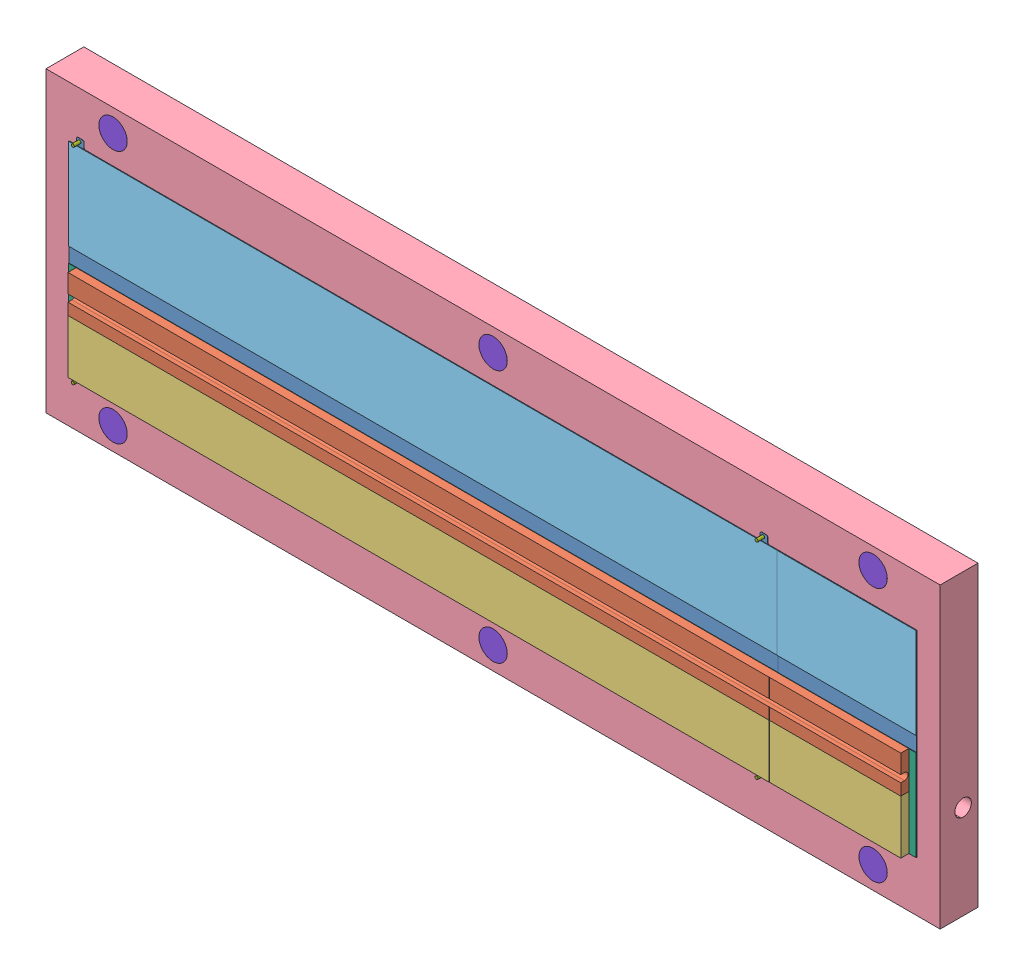
SolidWorks assembly IST Grind Fixture, configuration Default. Lengths in mm.
Overall size (600 200 31.36).
16 component instances, 8 part files, 35 mates.
Components (placement in the parent):
- Flattened Kapton-1: Flattened Kapton [Default] at (-288.1719 96.9459 86.2007) size (568.82 142.03 0.23)
- IST CFoam Stave rev 6_10-1: IST CFoam Stave rev 6_10 [Default] at (-8.6979 13.4546 89.4122) x (0 -1 0) z (1 0 0) size (25 5.5 558.8)
- IST Choneycomb Stave rev6_10-1: IST Choneycomb Stave rev6_10 [Default] at (-288.0979 -17.0454 89.4122) x (0 1 0) z (1 0 0) size (36 5.5 558.8)
- IST Grind Fixture-1: IST Grind Fixture [Default] at (-308.7819 -69.0041 60.8007) x (1 0 0) z (0 -1 0) size (600 25.4 200)
- IST CF skin rev 6_10 connector side-1: IST CF skin rev 6_10 connector side [Default] at (-8.7719 66.446 86.3622) x (-1 0 0) z (0 1 0) size (568.8 0.37 61)
- IST CF skin rev 6_10-1: IST CF skin rev 6_10 [Default] at (-8.7719 -4.554 86.6622) x (1 0 0) z (0 1 0) size (568.8 0.37 61)
- 2mm x 30mm pin-1: 2mm x 30mm pin [Default] at (172.6281 99.9459 90.8007) x (1 0 0) z (0 1 0) size (2 30 2)
- 2mm x 30mm pin-2: 2mm x 30mm pin [Default] at (172.6281 -38.0541 90.8007) x (1 0 0) z (0 1 0) size (2 30 2)
- 2mm x 30mm pin-3: 2mm x 30mm pin [Default] at (-286.1719 -38.0541 90.8007) x (1 0 0) z (0 1 0) size (2 30 2)
- 2mm x 30mm pin-4: 2mm x 30mm pin [Default] at (-286.1719 99.9459 90.8007) x (1 0 0) z (0 1 0) size (2 30 2)
- Steel Plug-1: Steel Plug [Default] at (246.2181 -54.0041 60.8007) x (1 0 0) z (0 -1 0) size (19.05 25.4 19.05)
- Steel Plug-2: Steel Plug [Default] at (-8.7819 -54.0041 60.8007) x (1 0 0) z (0 -1 0) size (19.05 25.4 19.05)
- Steel Plug-3: Steel Plug [Default] at (-263.7819 -54.0041 60.8007) x (1 0 0) z (0 -1 0) size (19.05 25.4 19.05)
- Steel Plug-4: Steel Plug [Default] at (-263.7819 115.9959 60.8007) x (1 0 0) z (0 -1 0) size (19.05 25.4 19.05)
- Steel Plug-5: Steel Plug [Default] at (-8.7819 115.9959 60.8007) x (1 0 0) z (0 -1 0) size (19.05 25.4 19.05)
- Steel Plug-6: Steel Plug [Default] at (246.2181 116.9959 60.8007) x (1 0 0) z (0 -1 0) size (19.05 25.4 19.05)
Mates (geometry in assembly coordinates):
- Distance1: distance = 0.076 mm anti-aligned: plane of IST CFoam Stave rev 6_10-1 through (182.4521 0.9546 92.1622) normal (1 0 0); plane of Flattened Kapton-1 through (182.5281 30.9503 86.4307) normal (-1 0 0)
- Distance2: distance = 0.076 mm anti-aligned: plane of IST Choneycomb Stave rev6_10-1 through (182.4521 -35.0454 86.6622) normal (1 0 0); plane of Flattened Kapton-1 through (182.5281 30.9503 86.4307) normal (-1 0 0)
- Coincident12: coincident aligned: plane of Flattened Kapton-1 through (-464.9409 -35.0454 86.3607) normal (0 -1 0); plane of IST Choneycomb Stave rev6_10-1 through (270.7021 -35.0454 92.1622) normal (0 -1 0)
- Coincident13: coincident anti-aligned: plane of IST CFoam Stave rev 6_10-1 through (250.7021 0.9546 86.6622) normal (0 -1 0); plane of IST Choneycomb Stave rev6_10-1 through (270.7021 0.9546 92.1622) normal (0 1 0)
- Coincident14: coincident anti-aligned: plane of Flattened Kapton-1 through (-464.9409 30.9503 86.2007) normal (0 0 -1); plane of IST Grind Fixture-1 through (-308.7819 130.9959 86.2007) normal (0 0 1)
- Concentric1: concentric aligned: cylinder of Flattened Kapton-1 through (172.6281 -38.0541 86.3607) axis (0 0 -1) radius 1; cylinder of IST Grind Fixture-1 through (172.6281 -38.0541 86.2007) axis (0 0 -1) radius 1
- Concentric2: concentric aligned: cylinder of Flattened Kapton-1 through (-286.1719 -38.0541 86.3607) axis (0 0 -1) radius 1; cylinder of IST Grind Fixture-1 through (-286.1719 -38.0541 86.2007) axis (0 0 -1) radius 1
- Coincident15: coincident anti-aligned: plane of Flattened Kapton-1 through (-464.9409 30.9503 86.4307) normal (0 0 1); plane of IST CF skin rev 6_10 connector side-1 through (275.6281 35.9459 86.4307) normal (0 0 -1)
- Coincident16: coincident aligned: plane of Flattened Kapton-1 through (275.6281 30.9503 86.4307) normal (1 0 0); plane of IST CF skin rev 6_10 connector side-1 through (275.6281 35.946 22.1671) normal (1 0 0)
- Coincident17: coincident aligned: plane of Flattened Kapton-1 through (-464.9409 96.946 86.4307) normal (0 1 0); plane of IST CF skin rev 6_10 connector side-1 through (255.6281 96.946 86.6622) normal (0 1 0)
- Coincident20: coincident anti-aligned: plane of Flattened Kapton-1 through (-464.9409 30.9503 86.4307) normal (0 0 1); plane of IST CF skin rev 6_10-1 through (275.6281 25.946 86.4307) normal (0 0 -1)
- Coincident21: coincident aligned: plane of Flattened Kapton-1 through (-464.9409 -35.054 86.3607) normal (0 -1 0); plane of IST CF skin rev 6_10-1 through (-273.1719 -35.054 86.3622) normal (0 -1 0)
- Coincident22: coincident aligned: plane of Flattened Kapton-1 through (275.6281 30.9503 86.4307) normal (1 0 0); plane of IST CF skin rev 6_10-1 through (275.6281 -35.054 150.8572) normal (1 0 0)
- Coincident24: coincident anti-aligned: plane of IST Choneycomb Stave rev6_10-1 through (270.7021 -35.0454 86.7307) normal (0 0 -1); plane of IST CF skin rev 6_10-1 through (182.3781 -128.3041 86.7307) normal (0 0 1)
- Coincident25: coincident anti-aligned: plane of IST CFoam Stave rev 6_10-1 through (270.7021 0.9546 86.7307) normal (0 0 -1); plane of IST CF skin rev 6_10-1 through (182.3781 -128.3041 86.7307) normal (0 0 1)
- Concentric3: concentric anti-aligned: cylinder of IST Grind Fixture-1 through (172.6281 99.9459 86.2007) axis (0 0 -1) radius 1; cylinder of 2mm x 30mm pin-1 through (172.6281 99.9459 60.8007) axis (0 0 1) radius 1
- Coincident26: coincident aligned: plane of IST Grind Fixture-1 through (-308.7819 130.9959 60.8007) normal (0 0 -1); plane of 2mm x 30mm pin-1 through (172.6281 99.9459 60.8007) normal (0 0 -1)
- Concentric4: concentric anti-aligned: cylinder of IST Grind Fixture-1 through (172.6281 -38.0541 86.2007) axis (0 0 -1) radius 1; cylinder of 2mm x 30mm pin-2 through (172.6281 -38.0541 60.8007) axis (0 0 1) radius 1
- Coincident27: coincident aligned: plane of IST Grind Fixture-1 through (-308.7819 130.9959 60.8007) normal (0 0 -1); plane of 2mm x 30mm pin-2 through (172.6281 -38.0541 60.8007) normal (0 0 -1)
- Concentric5: concentric anti-aligned: cylinder of IST Grind Fixture-1 through (-286.1719 -38.0541 86.2007) axis (0 0 -1) radius 1; cylinder of 2mm x 30mm pin-3 through (-286.1719 -38.0541 60.8007) axis (0 0 1) radius 1
- Coincident29: coincident aligned: plane of IST Grind Fixture-1 through (-308.7819 130.9959 60.8007) normal (0 0 -1); plane of 2mm x 30mm pin-3 through (-286.1719 -38.0541 60.8007) normal (0 0 -1)
- Concentric6: concentric anti-aligned: cylinder of IST Grind Fixture-1 through (-286.1719 99.9459 86.2007) axis (0 0 -1) radius 1; cylinder of 2mm x 30mm pin-4 through (-286.1719 99.9459 60.8007) axis (0 0 1) radius 1
- Coincident30: coincident aligned: plane of IST Grind Fixture-1 through (-308.7819 130.9959 60.8007) normal (0 0 -1); plane of 2mm x 30mm pin-4 through (-286.1719 99.9459 60.8007) normal (0 0 -1)
- Concentric7: concentric: cylinder of IST Grind Fixture-1 through (246.2181 -54.0041 60.8007) axis (0 0 1) radius 9.525; cylinder of Steel Plug-1 through (246.2181 -54.0041 29.9086) axis (0 0 -1) radius 9.525
- Coincident32: coincident aligned: plane of IST Grind Fixture-1 through (-308.7819 130.9959 60.8007) normal (0 0 -1); plane of Steel Plug-1 through (246.2181 -54.0041 60.8007) normal (0 0 -1)
- Concentric8: concentric: cylinder of IST Grind Fixture-1 through (-8.7819 -54.0041 60.8007) axis (0 0 1) radius 9.525; cylinder of Steel Plug-2 through (-8.7819 -54.0041 86.2007) axis (0 0 -1) radius 9.525
- Coincident33: coincident aligned: plane of IST Grind Fixture-1 through (-308.7819 130.9959 60.8007) normal (0 0 -1); plane of Steel Plug-2 through (-8.7819 -54.0041 60.8007) normal (0 0 -1)
- Concentric9: concentric: cylinder of IST Grind Fixture-1 through (-263.7819 -54.0041 60.8007) axis (0 0 1) radius 9.525; cylinder of Steel Plug-3 through (-263.7819 -54.0041 86.2007) axis (0 0 -1) radius 9.525
- Coincident34: coincident aligned: plane of IST Grind Fixture-1 through (-308.7819 130.9959 60.8007) normal (0 0 -1); plane of Steel Plug-3 through (-263.7819 -54.0041 60.8007) normal (0 0 -1)
- Concentric10: concentric: cylinder of IST Grind Fixture-1 through (-263.7819 115.9959 60.8007) axis (0 0 1) radius 9.525; cylinder of Steel Plug-4 through (-263.7819 115.9959 86.2007) axis (0 0 -1) radius 9.525
- Coincident35: coincident aligned: plane of IST Grind Fixture-1 through (-308.7819 130.9959 60.8007) normal (0 0 -1); plane of Steel Plug-4 through (-263.7819 115.9959 60.8007) normal (0 0 -1)
- Concentric11: concentric: cylinder of IST Grind Fixture-1 through (-8.7819 115.9959 60.8007) axis (0 0 1) radius 9.525; cylinder of Steel Plug-5 through (-8.7819 115.9959 86.2007) axis (0 0 -1) radius 9.525
- Coincident36: coincident aligned: plane of IST Grind Fixture-1 through (-308.7819 130.9959 60.8007) normal (0 0 -1); plane of Steel Plug-5 through (-8.7819 115.9959 60.8007) normal (0 0 -1)
- Concentric12: concentric: cylinder of IST Grind Fixture-1 through (246.2181 116.9959 60.8007) axis (0 0 1) radius 9.525; cylinder of Steel Plug-6 through (246.2181 116.9959 86.2007) axis (0 0 -1) radius 9.525
- Coincident37: coincident aligned: plane of IST Grind Fixture-1 through (-308.7819 130.9959 60.8007) normal (0 0 -1); plane of Steel Plug-6 through (246.2181 116.9959 60.8007) normal (0 0 -1)
